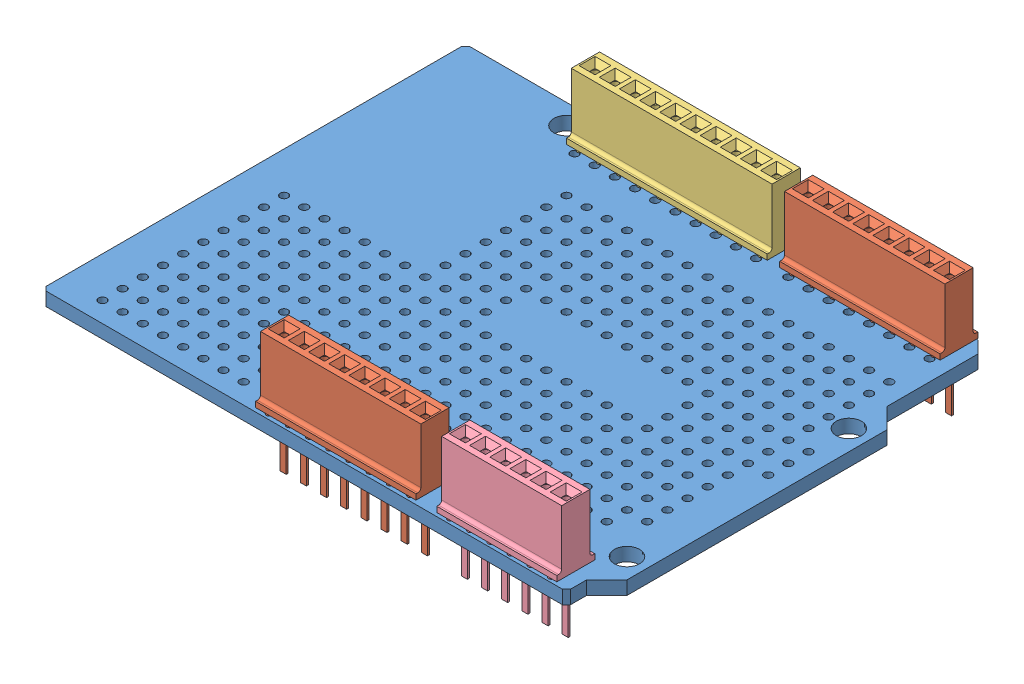
SolidWorks assembly DAC_Shield, configuration Default. Lengths in mm.
Overall size (68.58 15.62 53.34).
5 component instances, 4 part files, 6 mates.
Components (placement in the parent):
- Arduino proto shield R3-1: Arduino proto shield R3 [Default] at (-12.7768 38.9837 78.719) size (68.58 1.7 53.34)
- Berg Header Receptacle long-2: Berg Header Receptacle long [Default] at (24.0657 41.0139 76.177) size (20.2 15.62 4.78)
- Berg Header Receptacle long-3: Berg Header Receptacle long [Default] at (41.7939 41.0139 27.9175) size (20.2 15.62 4.78)
- Berg Header Receptacle 2.54 x 10 - FCI - 66951-010LF-1: Berg Header Receptacle 2.54 x 10 - FCI - 66951-010LF [Default] at (17.4767 41.0139 27.9087) size (25.28 15.62 4.78)
- Berg Header Receptacle 6-1: Berg Header Receptacle 6 [Default] at (46.9152 41.0139 76.2138) size (15.12 15.62 4.78)
Mates (geometry in assembly coordinates):
- Coincident2: coincident anti-aligned: plane of Arduino proto shield R3-1 through (-12.7768 40.6837 78.719) normal (0 1 0); plane of Berg Header Receptacle long-2 through (32.5859 40.6837 73.8518) normal (0 -1 0)
- Coincident3: coincident anti-aligned: plane of Arduino proto shield R3-1 through (-12.7768 40.6837 78.719) normal (0 1 0); plane of Berg Header Receptacle long-3 through (32.5341 40.6837 25.5923) normal (0 -1 0)
- Coincident4: coincident anti-aligned: plane of Arduino proto shield R3-1 through (-12.7768 40.6837 78.719) normal (0 1 0); plane of Berg Header Receptacle 2.54 x 10 - FCI - 66951-010LF-1 through (28.5369 40.6837 25.584) normal (0 -1 0)
- Coincident5: coincident anti-aligned: plane of Arduino proto shield R3-1 through (-12.7768 40.6837 78.719) normal (0 1 0); plane of Berg Header Receptacle 6-1 through (50.3554 40.6837 73.8886) normal (0 -1 0)
- Distance1: distance = 0.125 mm aligned: plane of Berg Header Receptacle 6-1 through (51.1062 41.081 76.0748) normal (1 0 0); cylinder of Arduino proto shield R3-1 through (50.7232 40.6837 76.179) axis (0 -1 0) radius 0.508
- Parallel1: parallel aligned: plane of Arduino proto shield R3-1 through (-12.2688 40.6837 78.719) normal (0 0 1); plane of Berg Header Receptacle 6-1 through (36.4149 41.942 77.9918) normal (0 0 1)
